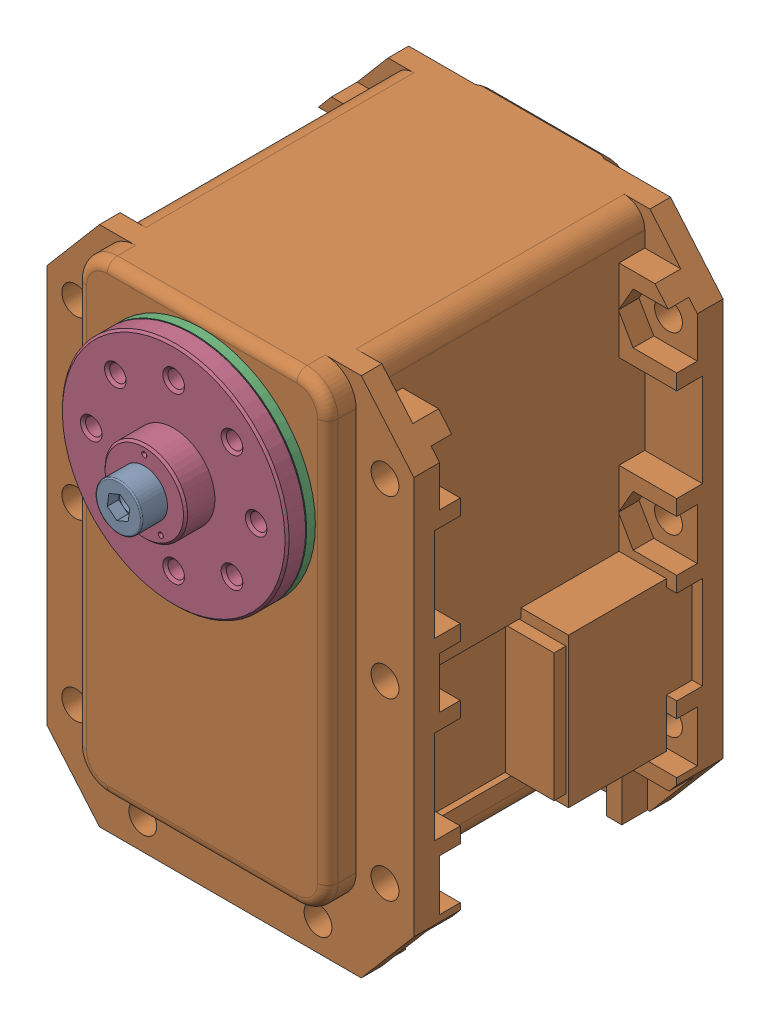
SolidWorks assembly MX-28(T)-4, configuration Default. Lengths in mm.
Overall size (35.6 54.13 45.1).
4 component instances, 4 part files, 0 mates.
Components (placement in the parent):
- WB_M2.5x8-1: WB_M2.5x8 [Default] at (0 0 25.85) x (0 0 -1) z (-0.991137 0.132843 0) size (10.5 4.5 4.5)
- dynamixel_x28series(Défaut)-1: dynamixel_x28series(Défaut) [Default] at origin size (35.6 50.71 41.85)
- trust_washer(Défaut)-1: trust_washer(Défaut) [Default] at (0 0 18.6) x (-0.666375 -0.745617 0) z (0.745617 -0.666375 0) size (22 0.85 22)
- HN07-N101(Défaut)-1: HN07-N101(Défaut) [Default] at (0 0 18.5) x (1 0 0) z (0 -1 0) size (22 5.85 22)
